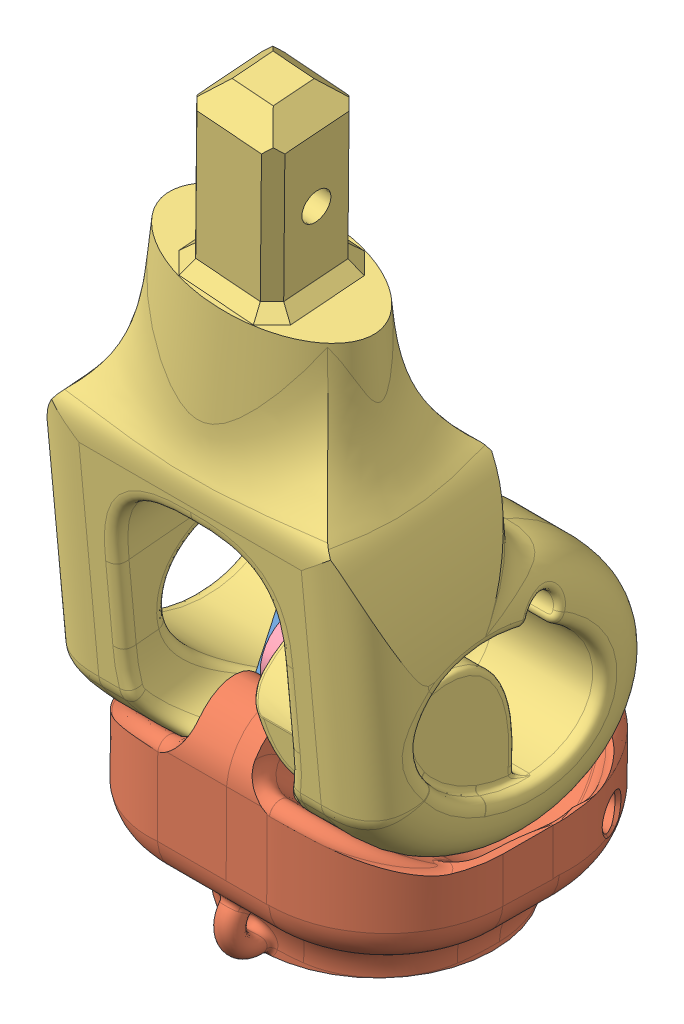
SolidWorks assembly Assem3 - LEFT, configuration Default. Lengths in mm.
Overall size (86.23 175.19 101.69).
4 component instances, 4 part files, 8 mates.
Components (placement in the parent):
- New link 1-2: New link 1 [Default] at (768.7127 139.4947 -280.4181) x (0 0.420158 0.907451) z (-1 0 0) size (15.95 67.39 6.35)
- Tibial head with hardware - bone connection - Latest - LEFT-2: Tibial head with hardware - bone connection - Latest - LEFT [Default] at (724.154 173.525 -349.8889) x (1 0 0) z (0 0.005389 0.999985) size (75.42 50.33 77.35)
- Femoral end with hardware - Latest - LEFT-2: Femoral end with hardware - Latest - LEFT [Default] at (775.1897 109.0215 -293.527) x (0 0.079175 -0.996861) z (1 0 0) size (85.37 492.51 102.79)
- Split link 2-3: Split link 2 [Default] at (768.5857 148.4489 -289.7745) x (0 -0.73925 0.673431) z (1 0 0) size (15.95 62.81 6.35)
Mates (geometry in assembly coordinates):
- Coincident11: coincident anti-aligned: plane of Tibial head with hardware - bone connection - Latest - LEFT-2 through (768.5857 125.887 -314.5415) normal (1 0 0); plane of Split link 2-3 through (768.5857 125.887 -314.5415) normal (-1 0 0)
- Concentric21: concentric anti-aligned: cylinder of Tibial head with hardware - bone connection - Latest - LEFT-2 through (730.6762 125.887 -314.5415) axis (1 0 0) radius 3.175; cylinder of Split link 2-3 through (774.9357 125.887 -314.5415) axis (-1 0 0) radius 3.937
- Coincident12: coincident anti-aligned: plane of New link 1-2 through (762.3627 174.0459 -296.4156) normal (-1 0 0); plane of Tibial head with hardware - bone connection - Latest - LEFT-2 through (762.3627 146.4551 -268.5576) normal (1 0 0)
- Concentric22: concentric aligned: cylinder of New link 1-2 through (762.3627 127.3711 -274.8048) axis (1 0 0) radius 3.937; cylinder of Tibial head with hardware - bone connection - Latest - LEFT-2 through (730.6762 127.3711 -274.8048) axis (1 0 0) radius 3.175
- Concentric23: concentric aligned: cylinder of New link 1-2 through (762.3627 174.0459 -296.4156) axis (1 0 0) radius 3.937; cylinder of Femoral end with hardware - Latest - LEFT-2 through (732.0097 174.0459 -296.4156) axis (1 0 0) radius 3.175
- Concentric24: concentric aligned: cylinder of Femoral end with hardware - Latest - LEFT-2 through (802.4947 157.446 -279.8981) axis (-1 0 0) radius 3.175; cylinder of Split link 2-3 through (774.9357 157.446 -279.8981) axis (-1 0 0) radius 3.937
- Distance1: distance = 0.254 mm anti-aligned: plane of Femoral end with hardware - Latest - LEFT-2 through (775.1897 122.5455 -335.6656) normal (-1 0 0); plane of Split link 2-3 through (774.9357 125.887 -314.5415) normal (1 0 0)
- LimitAngle1: limit planar angle = 0 rad anti-aligned: plane of Split link 2-3 through (774.9357 119.991 -309.1705) normal (0 -0.73925 0.673431); plane of Tibial head with hardware - bone connection - Latest - LEFT-2 through (852.114 123.9982 -304.7717) normal (0 0.73925 -0.673431)
